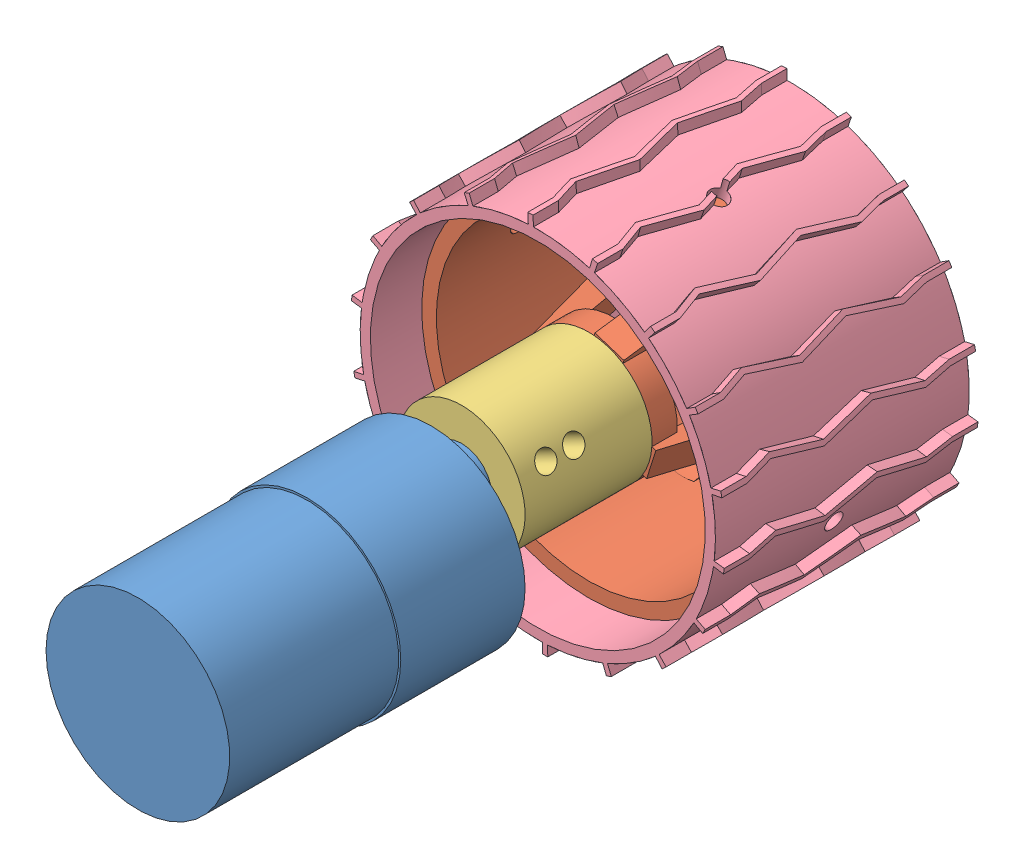
SolidWorks assembly Motor x Wheel Assembly, configuration Default. Lengths in mm.
Overall size (92.57 92.9 128.8).
4 component instances, 4 part files, 6 mates.
Components (placement in the parent):
- motor-1: motor [Default] at (-60.357 -3.1473 15.5878) size (37 37 78.8)
- wheel inner-1: wheel inner [Default] at (-60.357 3.3527 -15.4122) x (0.952401 -0.304848 0) z (0.304848 0.952401 0) size (65.75 39.75 65.75)
- wheel x motor connector test 2-1: wheel x motor connector test 2 [Default] at (-60.357 3.3527 9.5878) x (0.889009 0.457889 0) z (0 0 -1) size (25 25 25)
- wheel outer-1: wheel outer [Default] at (-60.357 3.3527 -55.4122) x (-0.304848 -0.952401 0) z (0 0 1) size (74.01 73.51 50)
Mates (geometry in assembly coordinates):
- Concentric1: concentric aligned: cylinder of motor-1 through (-60.357 3.3527 -5.4122) axis (0 0 1) radius 3; cylinder of wheel x motor connector test 2-1 through (-60.357 3.3527 6.5878) axis (0 0 1) radius 3.125
- Coincident1: coincident anti-aligned: plane of motor-1 through (-60.357 3.3527 -5.4122) normal (0 0 -1); plane of wheel x motor connector test 2-1 through (-60.357 3.3527 -5.4122) normal (0 0 1)
- Coincident2: coincident: circle of wheel inner-1; circle of wheel x motor connector test 2-1
- Coincident4: coincident: circle of wheel inner-1; circle of wheel x motor connector test 2-1
- Concentric2: concentric aligned: cylinder of wheel inner-1 through (-60.357 3.3527 -15.4122) axis (0 0 -1) radius 32.875; cylinder of wheel outer-1 through (-60.357 3.3527 -5.4122) axis (0 0 -1) radius 33
- Concentric3: concentric aligned: cylinder of wheel inner-1 through (-91.6681 13.3749 -30.4122) axis (0.952401 -0.304848 0) radius 1.75; cylinder of wheel outer-1 through (-38.4517 -3.6588 -30.4122) axis (0.952401 -0.304848 0) radius 1.75
